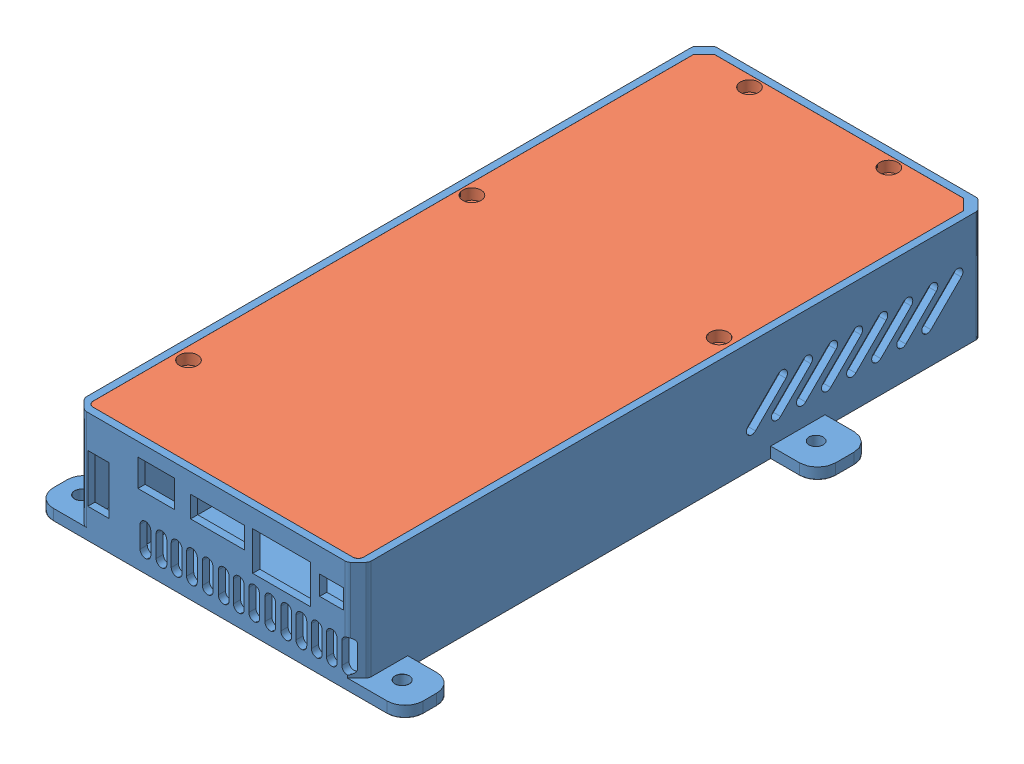
SolidWorks assembly 控制核心装配, configuration 默认. Lengths in mm.
Overall size (103.21 31 176.1).
2 component instances, 2 part files, 2 mates.
Components (placement in the parent):
- RK3588支架-1: RK3588支架 [Default] at (-205.8366 1.0768 164.1448) size (103.21 31 176.1)
- 盒子盖板-1: 盒子盖板 [默认] at (-12.7278 30.0639 186.9288) x (0 0 -1) z (1 0 0) size (172.1 5 75.51)
Mates (geometry in assembly coordinates):
- 重合1: coincident anti-aligned: plane of RK3588支架-1 through (32.9421 32.0768 90.0483) normal (0 0 1); plane of 盒子盖板-1 through (29.9421 32.0639 90.0483) normal (0 0 -1)
- 重合2: coincident anti-aligned: plane of RK3588支架-1 through (32.9421 32.0768 90.0483) normal (-1 0 0); plane of 盒子盖板-1 through (32.9421 32.0639 93.0483) normal (1 0 0)
